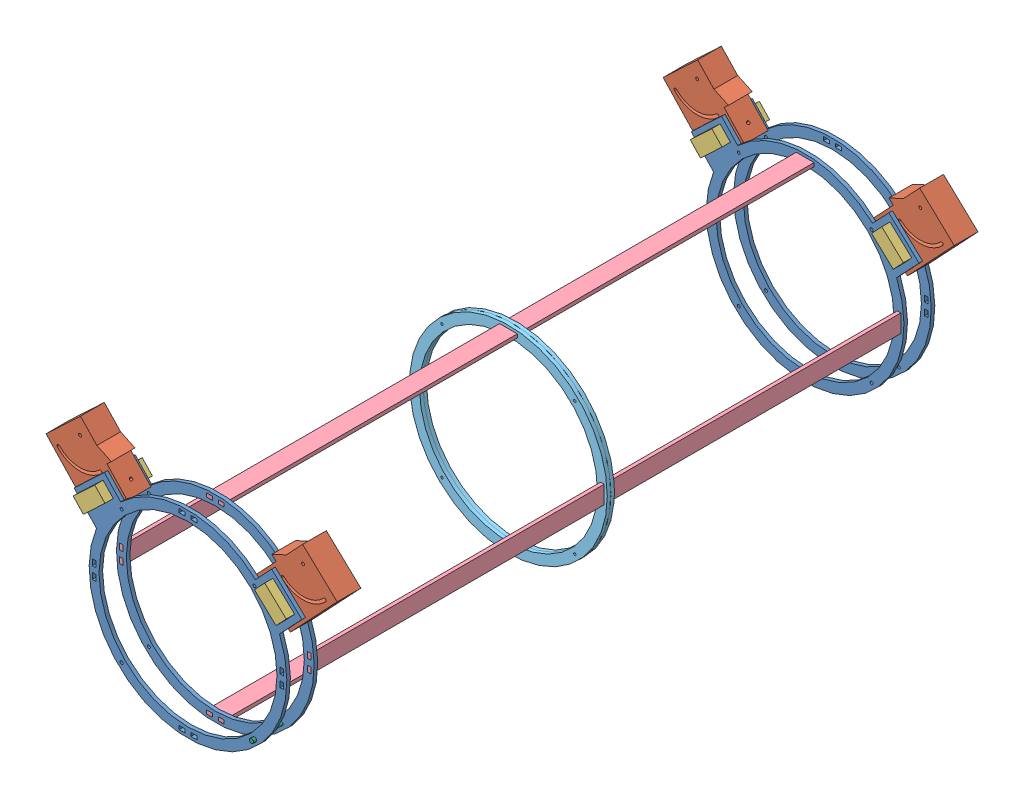
SolidWorks assembly Ensamblaje1, configuration Predeterminado. Lengths in mm.
Overall size (490.65 380.63 1120.05).
28 component instances, 7 part files, 7 mates.
Components (placement in the parent):
- Armado final_2-1: Armado final_2 [Predeterminado] at (317.9469 144.6933 560.0237) size (490.65 380.63 560.02)
  - Aramado-1: Aramado [Predeterminado] at (-348.9554 21.8342 490.6527) size (490.65 380.63 80.02)
    - Anillo acrilico-1: Anillo acrilico [Predeterminado] at (-159.8874 164.786 383.9345) size (383.93 333.2 6)
    - anclaje para base_1-3: anclaje para base_1 [Predeterminado] at (-195.9783 155.136 343.9345) x (0 0 -1) z (-0.685795 0.727795 0) size (40 90 115)
    - Anillo acrilico-2: Anillo acrilico [Predeterminado] at (-159.8874 164.786 337.9345) size (383.93 333.2 6)
    - anclaje para base_1-4: anclaje para base_1 [Predeterminado] at (184.5852 155.136 383.9345) x (0 0 1) z (0.685795 0.727795 0) size (40 90 115)
    - Pieza prisionera-1: Pieza prisionera [Predeterminado] at (-166.2782 137.2738 323.9284) x (-0.685795 0.727795 0) z (0 0 1) size (25 50 80)
    - Pieza prisionera-2: Pieza prisionera [Predeterminado] at (165.5199 127.2527 323.9108) x (0.685795 0.727795 0) z (0 0 1) size (25 50 80)
  - Barra anillo acrilico-1: Barra anillo acrilico [Predeterminado] at (-346.1008 189.0491 945.792) x (0 0 1) z (0 -1 0) size (500 30 6)
  - Barra anillo acrilico-2: Barra anillo acrilico [Predeterminado] at (-509.9512 19.1987 945.792) x (0 0 1) z (-1 0 0) size (500 30 6)
  - Barra anillo acrilico-3: Barra anillo acrilico [Predeterminado] at (-346.1008 -127.5494 945.792) x (0 0 1) z (0 -1 0) size (500 30 6)
  - Barra anillo acrilico-4: Barra anillo acrilico [Predeterminado] at (-193.3527 19.1987 945.792) x (0 0 1) z (-1 0 0) size (500 30 6)
  - Anillo acrilico intermedio-1: Anillo acrilico intermedio [Predeterminado] at (-508.8427 186.6202 1368.5873) size (333.2 333.2 6)
- Armado final_2-2: Armado final_2 [Predeterminado] at (-391.3569 144.6933 3309.1982) x (-1 0 0) z (0 0 -1) size (490.65 380.63 560.02)
  - Aramado-1: Aramado [Predeterminado] at (-348.9554 21.8342 490.6527) size (490.65 380.63 80.02)
    - Anillo acrilico-1: Anillo acrilico [Predeterminado] at (-159.8874 164.786 383.9345) size (383.93 333.2 6)
    - anclaje para base_1-3: anclaje para base_1 [Predeterminado] at (-195.9783 155.136 343.9345) x (0 0 -1) z (-0.685795 0.727795 0) size (40 90 115)
    - Anillo acrilico-2: Anillo acrilico [Predeterminado] at (-159.8874 164.786 337.9345) size (383.93 333.2 6)
    - anclaje para base_1-4: anclaje para base_1 [Predeterminado] at (184.5852 155.136 383.9345) x (0 0 1) z (0.685795 0.727795 0) size (40 90 115)
    - Pieza prisionera-1: Pieza prisionera [Predeterminado] at (-166.2782 137.2738 323.9284) x (-0.685795 0.727795 0) z (0 0 1) size (25 50 80)
    - Pieza prisionera-2: Pieza prisionera [Predeterminado] at (165.5199 127.2527 323.9108) x (0.685795 0.727795 0) z (0 0 1) size (25 50 80)
  - Barra anillo acrilico-1: Barra anillo acrilico [Predeterminado] at (-346.1008 189.0491 945.792) x (0 0 1) z (0 -1 0) size (500 30 6)
  - Barra anillo acrilico-2: Barra anillo acrilico [Predeterminado] at (-509.9512 19.1987 945.792) x (0 0 1) z (-1 0 0) size (500 30 6)
  - Barra anillo acrilico-3: Barra anillo acrilico [Predeterminado] at (-346.1008 -127.5494 945.792) x (0 0 1) z (0 -1 0) size (500 30 6)
  - Barra anillo acrilico-4: Barra anillo acrilico [Predeterminado] at (-193.3527 19.1987 945.792) x (0 0 1) z (-1 0 0) size (500 30 6)
  - Anillo acrilico intermedio-1: Anillo acrilico intermedio [Predeterminado] at (-508.8427 186.6202 1368.5873) size (333.2 333.2 6)
- tornillo-1: tornillo [Predeterminado] at (92.503 53.0668 2420.6109) size (7.24 7.24 65)
- Rosca-1: Rosca [Predeterminado] at (75.2295 60.5087 2423.6109) x (1 0 0) z (0 -1 0) size (6.9 5 6.9)
Mates (geometry in assembly coordinates):
- Coincidente1: coincident anti-aligned: plane of Armado final_2-1/Anillo acrilico intermedio-1 through (-190.8958 331.3135 1934.6109) normal (0 0 1); plane of Armado final_2-2/Anillo acrilico intermedio-1 through (117.4858 331.3135 1934.6109) normal (0 0 -1)
- Coincidente2: coincident anti-aligned: circle of Armado final_2-1/Anillo acrilico intermedio-1; circle of Armado final_2-2/Anillo acrilico intermedio-1
- Coincidente3: coincident anti-aligned: circle of Armado final_2-1/Anillo acrilico intermedio-1; circle of Armado final_2-2/Anillo acrilico intermedio-1
- Concéntrica1: concentric aligned: cylinder of Armado final_2-2/Aramado-1/Anillo acrilico-2 through (75.2295 60.5087 2484.6109) axis (0 0 -1) radius 2.475; cylinder of tornillo-1 through (75.2295 60.5087 2480.6109) axis (0 0 -1) radius 2.45
- Coincidente4: coincident anti-aligned: plane of Armado final_2-2/Aramado-1/Anillo acrilico-2 through (117.4858 331.3135 2480.6109) normal (0 0 1); plane of tornillo-1 through (92.503 53.0668 2480.6109) normal (0 0 -1)
- Coincidente5: coincident anti-aligned: cylinder of tornillo-1 through (75.2295 60.5087 2480.6109) axis (0 0 -1) radius 2.45; circle of Rosca-1
- Coincidente6: coincident anti-aligned: plane of Armado final_2-2/Aramado-1/Anillo acrilico-1 through (117.4858 331.3135 2428.6109) normal (0 0 -1); plane of Rosca-1 through (75.2295 60.5087 2428.6109) normal (0 0 1)
